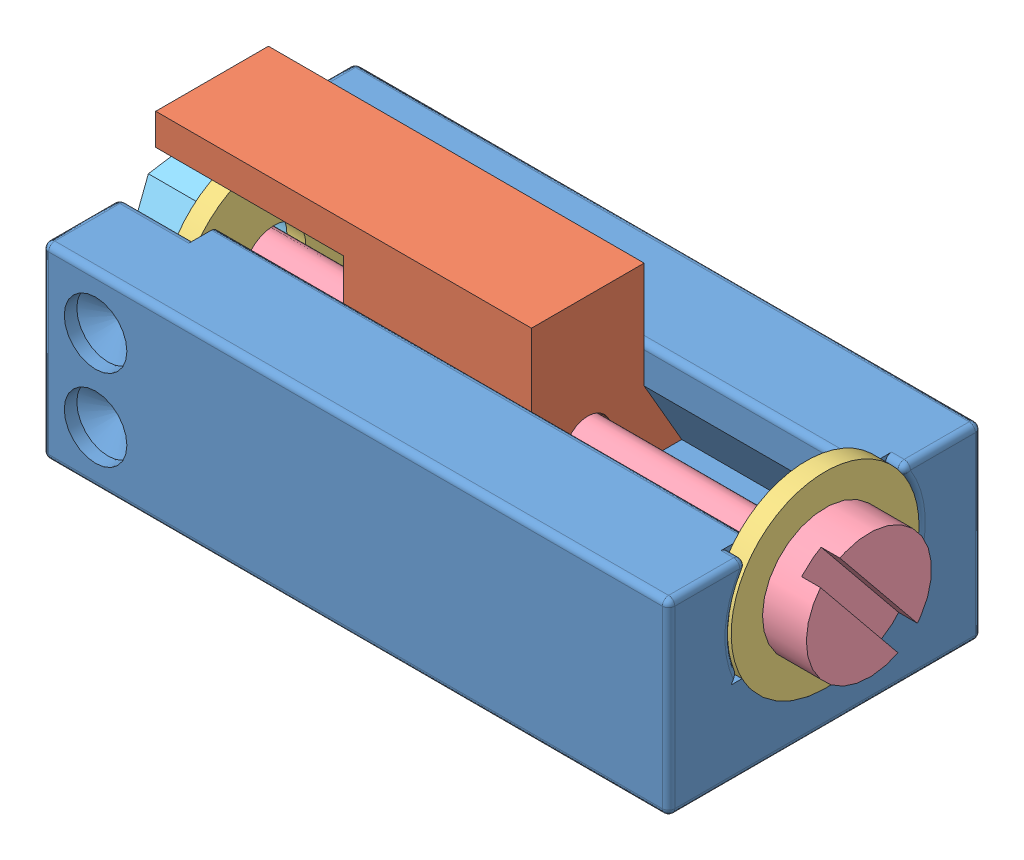
SolidWorks assembly Assem1, configuration Default. Lengths in mm.
Overall size (10.71 4.1 5).
6 component instances, 5 part files, 14 mates.
Components (placement in the parent):
- drive-1: drive [Default] at origin size (10.02 3 5)
- shuttle-1: shuttle [Default] at (3.2106 2.3608 2.5) x (1 0 0) z (0 -1 0) size (6 3 2.74)
- washer_m1-1: washer_m1 [Default] at (9.7 3.0608 2.5) x (0 0.299575 -0.954073) z (0 -0.954073 -0.299575) size (3 0.3 3)
- screw_m1x10-1: screw_m1x10 [Default] at (10.7 3.0608 2.5) x (0 0.631255 -0.775575) z (-1 0 0) size (2 2 10.7)
- washer_m1-2: washer_m1 [Default] at (0.9 3.0608 2.5) x (0 -0.98456 -0.175045) z (0 -0.175045 0.98456) size (3 0.3 3)
- nut-2: nut [Default] at (0.9 3.0608 2.5) x (0 -0.778085 -0.628159) z (0 0.628159 -0.778085) size (2.89 0.8 2.5)
Mates (geometry in assembly coordinates):
- Coincident2: coincident anti-aligned: plane of drive-1 through (0 2.3222 4.0222) normal (0 -0.5 -0.866025); plane of shuttle-1 through (6.2106 3.0103 3.625) normal (0 0.5 0.866025)
- Concentric1: concentric anti-aligned: cylinder of drive-1 through (9.7 3.0608 2.5) axis (1 0 0) radius 1.5; cylinder of washer_m1-1 through (10 3.0608 2.5) axis (-1 0 0) radius 1.5
- Coincident3: coincident anti-aligned: plane of drive-1 through (9.7 3.0608 2.5) normal (1 0 0); plane of washer_m1-1 through (9.7 3.0608 2.5) normal (-1 0 0)
- Concentric2: concentric anti-aligned: cylinder of screw_m1x10-1 through (0 3.0608 2.5) axis (1 0 0) radius 0.35; cylinder of shuttle-1 through (3.2106 3.0608 2.5) axis (-1 0 0) radius 0.375
- Coincident4: coincident anti-aligned: plane of washer_m1-1 through (10 3.0608 2.5) normal (1 0 0); plane of screw_m1x10-1 through (10 3.0608 2.5) normal (-1 0 0)
- Coincident5: coincident anti-aligned: plane of drive-1 through (1.2 3.0608 2.5) normal (-1 0 0); plane of washer_m1-2 through (1.2 3.0608 2.5) normal (1 0 0)
- Concentric3: concentric aligned: cylinder of drive-1 through (1.2 3.0608 2.5) axis (-1 0 0) radius 1.5; cylinder of washer_m1-2 through (1.2 3.0608 2.5) axis (-1 0 0) radius 1.5
- Concentric4: concentric anti-aligned: cylinder of drive-1 through (9.7 3.0608 2.5) axis (1 0 0) radius 1.5; cylinder of washer_m1-1 through (10 3.0608 2.5) axis (-1 0 0) radius 1.5
- Coincident6: coincident anti-aligned: plane of drive-1 through (9.7 3.0608 2.5) normal (1 0 0); plane of washer_m1-1 through (9.7 3.0608 2.5) normal (-1 0 0)
- Parallel1: parallel anti-aligned: plane of drive-1 through (0 0 1.6) normal (0 0 1); plane of shuttle-1 through (6.2106 2.3608 1.6) normal (0 0 -1)
- Coincident8: coincident anti-aligned: plane of drive-1 through (0 2.3222 4.0222) normal (0 -0.5 -0.866025); plane of shuttle-1 through (6.2106 3.0103 3.625) normal (0 0.5 0.866025)
- Coincident9: coincident anti-aligned: plane of drive-1 through (0 0.1572 -0.2722) normal (0 -0.5 0.866025); plane of shuttle-1 through (6.2106 3.0103 1.375) normal (0 0.5 -0.866025)
- Concentric5: concentric aligned: cylinder of screw_m1x10-1 through (0 3.0608 2.5) axis (1 0 0) radius 0.35; cylinder of nut-2 through (0.1 3.0608 2.5) axis (1 0 0) radius 0.55
- Coincident10: coincident anti-aligned: plane of washer_m1-2 through (0.9 3.0608 2.5) normal (-1 0 0); plane of nut-2 through (0.9 3.0608 2.5) normal (1 0 0)
